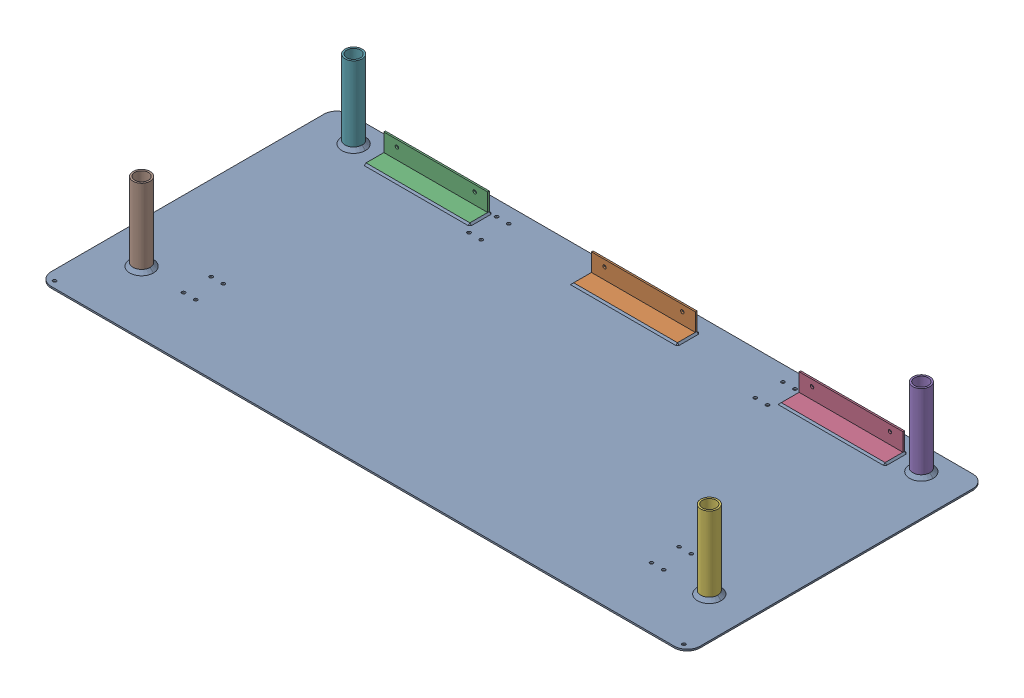
SolidWorks assembly GE-16053_ASM, configuration Default. Lengths in mm.
Overall size (1270 155.57 584.2).
9 component instances, 4 part files, 0 mates.
Components (placement in the parent):
- GE-16053_ASM-1: GE-16053_ASM [Default] at origin size (1157.44 6.44 461.85)
- GE-16016-1: GE-16016 [Default] at origin size (1270 3.17 584.2)
- GE-16053-01-1: GE-16053-01 [Default] at (0 3.175 -260.35) x (-1 0 0) z (0 0 -1) size (203.2 38.1 38.1)
- GE-16053-01-2: GE-16053-01 [Default] at (-406.4 3.175 -260.35) x (-1 0 0) z (0 0 -1) size (203.2 38.1 38.1)
- GE-16053-01-3: GE-16053-01 [Default] at (406.4 3.175 -260.35) x (-1 0 0) z (0 0 -1) size (203.2 38.1 38.1)
- GE-16053-02-1: GE-16053-02 [Default] at (555.625 79.375 -245.618) size (33.4 152.4 33.4)
- GE-16053-02-2: GE-16053-02 [Default] at (555.625 79.375 169.418) size (33.4 152.4 33.4)
- GE-16053-02-3: GE-16053-02 [Default] at (-555.625 79.375 -245.618) size (33.4 152.4 33.4)
- GE-16053-02-4: GE-16053-02 [Default] at (-555.625 79.375 169.418) size (33.4 152.4 33.4)
